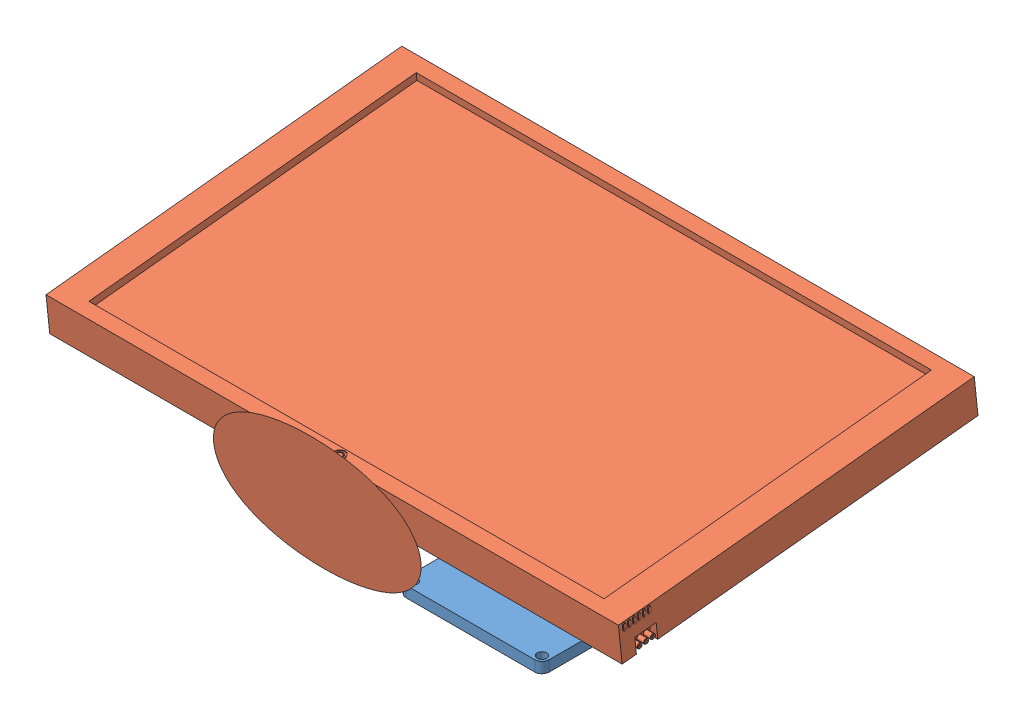
SolidWorks assembly BASE Y TELEVISIÓN, configuration Predeterminado. Lengths in mm.
Overall size (801.5 360.52 521.46).
2 component instances, 2 part files, 2 mates.
Components (placement in the parent):
- BASE P- TELEVISOÓN-1: BASE P- TELEVISOÓN [Predeterminado] at (-16.8304 -62.0323 200) size (200 145 200)
- User Library-Televisión-1: User Library-Televisión [Predeterminado] at (-16.8304 222.6511 239.2538) x (1 0 0) z (0 0.994532 0.104431) size (801.5 500 231.64)
Mates (geometry in assembly coordinates):
- Concéntrica1: concentric aligned: cylinder of BASE P- TELEVISOÓN-1 through (-69.8304 63.8827 200) axis (1 0 0) radius 12.8049; cylinder of User Library-Televisión-1 through (-65.32 63.8827 200) axis (1 0 0) radius 8.434
- Ancho1: width aligned: plane of User Library-Televisión-1 through (-56.3408 148.1444 144.207) normal (-1 0 0); plane of User Library-Televisión-1 through (22.68 148.1444 144.207) normal (1 0 0); plane of BASE P- TELEVISOÓN-1 through (-51.8304 82.9677 170) normal (-1 0 0); plane of BASE P- TELEVISOÓN-1 through (18.1696 82.9677 170) normal (1 0 0)
